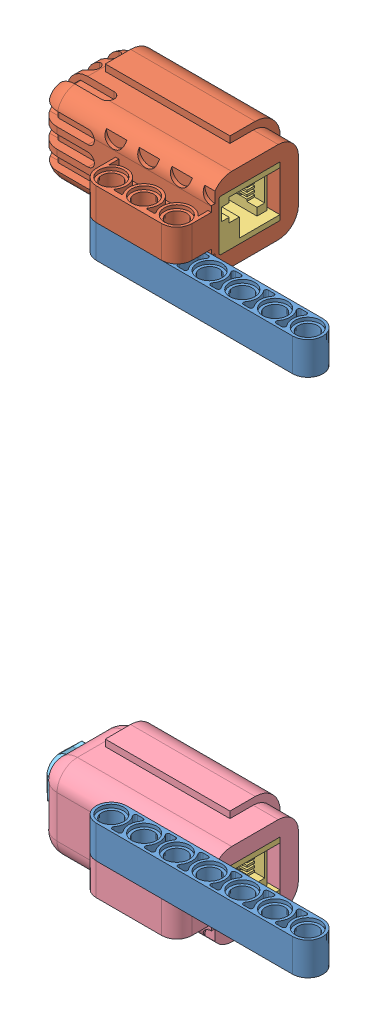
SolidWorks assembly Mantis step 17, configuration Simplified. Lengths in mm.
Overall size (81.16 168.01 31.6).
11 component instances, 6 part files, 28 mates.
Components (placement in the parent):
- beam_7-1: beam_7 [Default] at (-28.9114 -2.8807 1.7063) size (55.83 8.06 7.44)
- sensor_sound-1: sensor_sound [Default] at (-30.5614 9.1093 -13.8037) x (0 -1 0) z (0 0 1) size (24.03 45.21 31.6)
- socket-1: socket [Default] at (-9.0614 9.1093 -12.4537) x (0 1 0) z (-1 0 0) size (12.5 15 12.59)
- conn_3-1: conn_3 [Default] at (-12.7814 7.8744 1.7063) x (0.761842 0 -0.647763) z (0.647763 0 0.761842) size (6.15 24.2 6.07) (suppressed, hidden)
- conn_3-2: conn_3 [Default] at (-28.9114 8.4457 1.7063) x (0.990141 0 0.140072) z (-0.140072 0 0.990141) size (6.15 24.2 6.07) (suppressed, hidden)
- beam_7-2: beam_7 [Default] at (-28.9114 -130.9457 1.7063) size (55.83 8.06 7.44)
- sensor_touch_body-1: sensor_touch_body [Default] at (-30.5614 -134.8707 -13.8037) x (0 -1 0) z (0 0 1) size (24.05 45.24 31.6)
- socket-2: socket [Default] at (-9.0614 -134.8707 -12.4537) x (0 1 0) z (-1 0 0) size (12.5 15 12.59)
- sensor_touch_button-2: sensor_touch_button [Default] at (-48.0614 -134.8457 -13.8112) x (0 1 0) z (0 0 1) size (16.15 9.9 16.15)
- conn_3-3: conn_3 [Default] at (-28.9114 -134.7957 1.7063) x (1 0 0) z (0 0 -1) size (6.15 24.2 6.07) (suppressed, hidden)
- conn_3-4: conn_3 [Default] at (-12.7814 -134.5588 1.7063) x (-0.853339 0 -0.521356) z (-0.521356 0 0.853339) size (6.15 24.2 6.07) (suppressed, hidden)
Mates (geometry in assembly coordinates):
- Concentric1: concentric anti-aligned: cylinder of beam_7-1 through (-12.7814 -2.0657 1.7063) axis (0 1 0) radius 2.39; cylinder of sensor_sound-1 through (-12.7814 12.2193 1.7063) axis (0 -1 0) radius 2.39
- Concentric2: concentric anti-aligned: cylinder of beam_7-1 through (-28.9114 -2.0657 1.7063) axis (0 1 0) radius 2.39; cylinder of sensor_sound-1 through (-28.9114 12.2193 1.7063) axis (0 -1 0) radius 2.39
- Coincident1: coincident anti-aligned: plane of beam_7-1 through (-33.748 5.1843 5.5751) normal (0 1 0); plane of sensor_sound-1 through (-33.1028 5.1843 -3.2437) normal (0 -1 0)
- Parallel1: parallel anti-aligned: plane of sensor_sound-1 through (-21.8114 15.3593 -20.2437) normal (0 -1 0); plane of socket-1 through (-21.5614 15.3593 -19.9537) normal (0 1 0)
- Parallel2: parallel anti-aligned: plane of sensor_sound-1 through (-21.8114 15.0893 -4.9537) normal (0 0 -1); plane of socket-1 through (-21.5614 2.8593 -4.9537) normal (0 0 1)
- Coincident4: coincident anti-aligned: plane of sensor_sound-1 through (-21.8114 15.0893 -4.9537) normal (0 0 -1); plane of socket-1 through (-21.5614 2.8593 -4.9537) normal (0 0 1)
- Coincident5: coincident anti-aligned: plane of sensor_sound-1 through (-21.8114 15.3593 -20.2437) normal (0 -1 0); plane of socket-1 through (-21.5614 15.3593 -19.9537) normal (0 1 0)
- Concentric3: concentric anti-aligned: cylinder of sensor_sound-1 through (-28.9114 12.2193 1.7063) axis (0 -1 0) radius 2.39; cylinder of conn_3-2 through (-28.9114 13.2607 1.7063) axis (0 1 0) radius 2.39
- Concentric4: concentric anti-aligned: cylinder of sensor_sound-1 through (-12.7814 12.2193 1.7063) axis (0 -1 0) radius 2.39; cylinder of conn_3-1 through (-12.7814 -3.4106 1.7063) axis (0 1 0) radius 2.39
- Lock1: lock: unknown of sensor_sound-1; unknown of conn_3-2
- Lock2: lock: unknown of sensor_sound-1; unknown of conn_3-1
- Coincident6: coincident anti-aligned: plane of socket-2 through (-21.5614 -141.1207 -19.9537) normal (0 -1 0); plane of sensor_touch_body-1 through (-21.8114 -141.1207 -5.1637) normal (0 1 0)
- Coincident7: coincident anti-aligned: plane of sensor_touch_body-1 through (-21.8114 -128.8907 -4.9537) normal (0 0 -1); plane of socket-2 through (-21.5614 -141.1207 -4.9537) normal (0 0 1)
- Coincident8: coincident anti-aligned: plane of sensor_touch_body-1 through (-21.5614 -128.3707 -4.6537) normal (1 0 0); plane of socket-2 through (-21.5614 -141.1207 -19.9537) normal (-1 0 0)
- Coincident10: coincident anti-aligned: plane of sensor_touch_body-1 through (-41.8614 -133.8707 -19.2416) normal (0 -1 0); plane of sensor_touch_button-2 through (-47.8894 -133.8707 -20.9826) normal (0 1 0)
- Lock3: lock: unknown of ?; unknown of ?
- Concentric7: concentric aligned: cylinder of sensor_touch_body-1 through (-12.7814 -131.7607 1.7063) axis (0 -1 0) radius 2.39; circle of beam_7-2
- Concentric9: concentric anti-aligned: cylinder of beam_7-2 through (-28.9114 -130.1307 1.7063) axis (0 1 0) radius 2.39; cylinder of sensor_touch_body-1 through (-28.9114 -131.7607 1.7063) axis (0 -1 0) radius 2.39
- Coincident13: coincident anti-aligned: plane of beam_7-2 through (-33.748 -130.9457 5.5751) normal (0 -1 0); plane of sensor_touch_body-1 through (-8.59 -130.9457 -3.2437) normal (0 1 0)
- Concentric10: concentric anti-aligned: cylinder of beam_7-2 through (-28.9114 -130.1307 1.7063) axis (0 1 0) radius 2.39; cylinder of conn_3-3 through (-28.9114 -123.5107 1.7063) axis (0 -1 0) radius 2.39
- Concentric11: concentric anti-aligned: cylinder of beam_7-2 through (-12.7814 -130.1307 1.7063) axis (0 1 0) radius 2.39; cylinder of conn_3-4 through (-12.7814 -123.2738 1.7063) axis (0 -1 0) radius 2.39
- Coincident14: coincident anti-aligned: plane of sensor_touch_body-1 through (-9.2608 -137.9807 4.9043) normal (0 -1 0); plane of conn_3-3 through (-32.1094 -137.9807 -1.4492) normal (0 1 0)
- Lock4: lock: unknown of ?; unknown of ?
- Distance1: distance = 120 mm anti-aligned: plane of beam_7-2 through (-33.748 -122.8807 5.5751) normal (0 1 0); plane of beam_7-1 through (-33.748 -2.8807 5.5751) normal (0 -1 0)
- Concentric13: concentric aligned: cylinder of beam_7-1 through (11.4136 -2.0657 1.7063) axis (0 1 0) radius 2.39; cylinder of beam_7-2 through (11.4136 -130.1307 1.7063) axis (0 1 0) radius 2.39
- Coincident15: coincident aligned: plane of sensor_sound-1 through (-9.0614 19.6965 2.2311) normal (1 0 0); plane of socket-1 through (-9.0614 2.8593 -19.9537) normal (1 0 0)
- Parallel3: parallel aligned: plane of beam_7-1 through (20.4464 -3.042 -2.0137) normal (0 0 -1); plane of beam_7-2 through (20.4464 -131.107 -2.0137) normal (0 0 -1)
- Parallel4: parallel anti-aligned: plane of conn_3-3 through (-28.9114 -134.7957 1.7063) normal (0 0 -1); plane of assembly through (0 0 0) normal (0 0 1)
